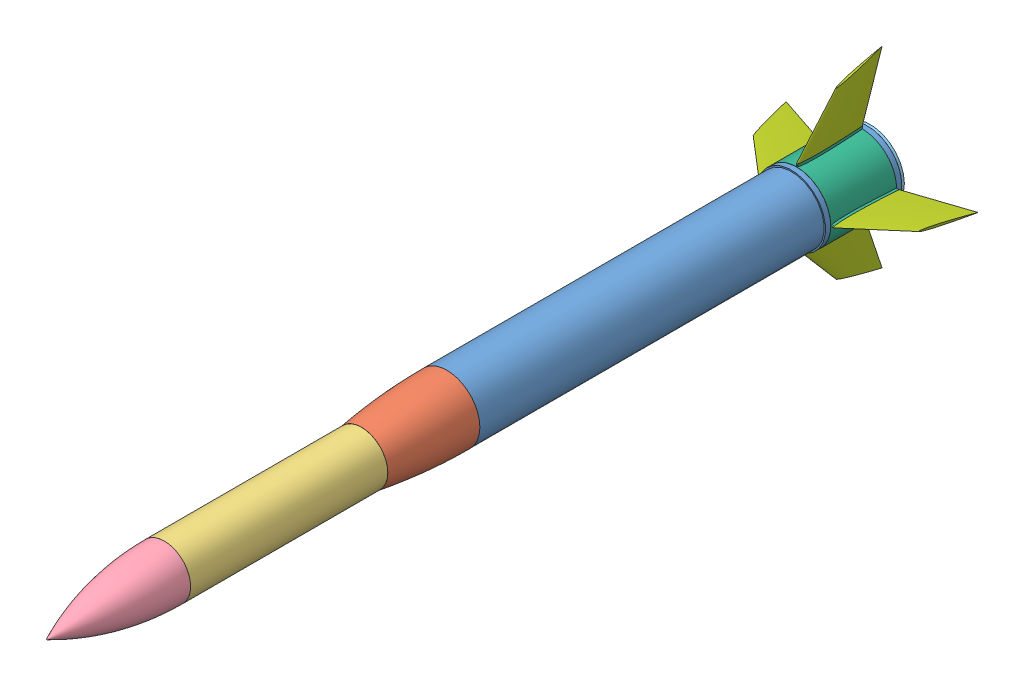
SolidWorks assembly Multi, configuration Default. Lengths in mm.
Overall size (146.83 146.83 636.42).
10 component instances, 7 part files, 22 mates.
Components (placement in the parent):
- Lower Body Tube-1: Lower Body Tube [Default] at (145.1733 218.1659 197.2864) size (52 52 320)
- Transition-1: Transition [Default] at (145.1733 218.1659 597.2864) size (50 50 95)
- Upper Body Tube-1: Upper Body Tube [Default] at (145.1733 218.1659 582.2864) size (40 40 150)
- Nose Cone-1: Nose Cone [Default] at (145.1733 218.1659 822.2864) size (40 40 105)
- Motor Mount-1: Motor Mount [Default] at (145.1733 218.1659 195.2864) size (52 52 301)
- Fin Ring-1: Fin Ring [Default] at (145.1733 218.1659 251.2864) x (-1 0 0) z (0 0 -1) size (56 56 53.05)
- Fins-1: Fins [Default] at (145.1733 246.1659 251.2864) size (3 46.42 65.42)
- Fins-2: Fins [Default] at (173.1733 218.1659 251.2864) x (0 -1 0) z (0 0 1) size (3 46.42 65.42)
- Fins-3: Fins [Default] at (145.1733 190.1659 251.2864) x (-1 0 0) z (0 0 1) size (3 46.42 65.42)
- Fins-4: Fins [Default] at (117.1733 218.1659 251.2864) x (0 1 0) z (0 0 1) size (3 46.42 65.42)
Mates (geometry in assembly coordinates):
- Concentric1: concentric anti-aligned: cylinder of Lower Body Tube-1 through (145.1733 218.1659 517.2864) axis (0 0 -1) radius 23; cylinder of Transition-1 through (145.1733 218.1659 597.2864) axis (0 0 1) radius 23
- Coincident1: coincident anti-aligned: plane of Lower Body Tube-1 through (145.1733 218.1659 517.2864) normal (0 0 1); plane of Transition-1 through (145.1733 243.1659 517.2864) normal (0 0 -1)
- Concentric2: concentric anti-aligned: cylinder of Transition-1 through (145.1733 218.1659 597.2864) axis (0 0 1) radius 18; cylinder of Upper Body Tube-1 through (145.1733 218.1659 732.2864) axis (0 0 -1) radius 18
- Coincident2: coincident anti-aligned: plane of Transition-1 through (145.1733 238.1659 582.2864) normal (0 0 1); plane of Upper Body Tube-1 through (145.1733 218.1659 582.2864) normal (0 0 -1)
- Concentric3: concentric aligned: cylinder of Upper Body Tube-1 through (145.1733 218.1659 732.2864) axis (0 0 -1) radius 18; cylinder of Nose Cone-1 through (145.1733 218.1659 717.2864) axis (0 0 -1) radius 18
- Coincident3: coincident anti-aligned: plane of Upper Body Tube-1 through (145.1733 218.1659 732.2864) normal (0 0 1); plane of Nose Cone-1 through (145.1733 238.1659 732.2864) normal (0 0 -1)
- Concentric4: concentric aligned: cylinder of Lower Body Tube-1 through (145.1733 218.1659 517.2864) axis (0 0 -1) radius 23; cylinder of Motor Mount-1 through (145.1733 218.1659 495.2864) axis (0 0 -1) radius 20
- Coincident4: coincident anti-aligned: plane of Lower Body Tube-1 through (145.1733 218.1659 197.2864) normal (0 0 -1); plane of Motor Mount-1 through (145.1733 218.1659 197.2864) normal (0 0 1)
- Concentric5: concentric: cylinder of Lower Body Tube-1 through (145.1733 218.1659 517.2864) axis (0 0 -1) radius 25; cylinder of Fin Ring-1 through (145.1733 218.1659 201.2864) axis (0 0 1) radius 25
- Coincident5: coincident: plane of Lower Body Tube-1 through (145.1733 218.1659 251.2864) normal (0 0 -1); plane of Fin Ring-1 through (145.1733 218.1659 251.2864) normal (0 0 1)
- Coincident6: coincident: plane of Fin Ring-1 through (145.7733 245.1659 221.2864) normal (-0.980581 -0.196116 0); plane of Fins-1 through (145.5733 246.1659 221.2864) normal (0.980581 0.196116 0)
- Coincident7: coincident: plane of Fin Ring-1 through (144.5733 245.1659 221.2864) normal (0 1 0); plane of Fins-1 through (144.5733 245.1659 221.2864) normal (0 -1 0)
- Coincident8: coincident: plane of Fin Ring-1 through (145.1733 218.1659 221.2864) normal (0 0 1); plane of Fins-1 through (145.1733 246.1659 221.2864) normal (0 0 -1)
- Coincident9: coincident: plane of Fin Ring-1 through (172.1733 217.5659 221.2864) normal (-0.196116 0.980581 0); plane of Fins-2 through (173.1733 217.7659 221.2864) normal (0.196116 -0.980581 0)
- Coincident10: coincident: plane of Fin Ring-1 through (172.1733 218.7659 221.2864) normal (1 0 0); plane of Fins-2 through (172.1733 218.7659 221.2864) normal (-1 0 0)
- Coincident11: coincident: plane of Fin Ring-1 through (145.1733 218.1659 221.2864) normal (0 0 1); plane of Fins-2 through (173.1733 218.1659 221.2864) normal (0 0 -1)
- Coincident12: coincident: plane of Fin Ring-1 through (144.5733 191.1659 221.2864) normal (0.980581 0.196116 0); plane of Fins-3 through (144.7733 190.1659 221.2864) normal (-0.980581 -0.196116 0)
- Coincident13: coincident: plane of Fin Ring-1 through (145.7733 191.1659 221.2864) normal (0 -1 0); plane of Fins-3 through (145.7733 191.1659 221.2864) normal (0 1 0)
- Coincident14: coincident anti-aligned: plane of Fin Ring-1 through (145.1733 218.1659 221.2864) normal (0 0 1); plane of Fins-3 through (145.1733 190.1659 221.2864) normal (0 0 -1)
- Coincident15: coincident: plane of Fin Ring-1 through (117.1733 217.7659 221.2864) normal (0.196116 0.980581 0); plane of Fins-4 through (118.1733 217.5659 221.2864) normal (-0.196116 -0.980581 0)
- Coincident16: coincident: plane of Fin Ring-1 through (118.1733 217.5659 221.2864) normal (-1 0 0); plane of Fins-4 through (118.1733 217.5659 221.2864) normal (1 0 0)
- Coincident17: coincident anti-aligned: plane of Fin Ring-1 through (145.1733 218.1659 221.2864) normal (0 0 1); plane of Fins-4 through (117.1733 218.1659 221.2864) normal (0 0 -1)
